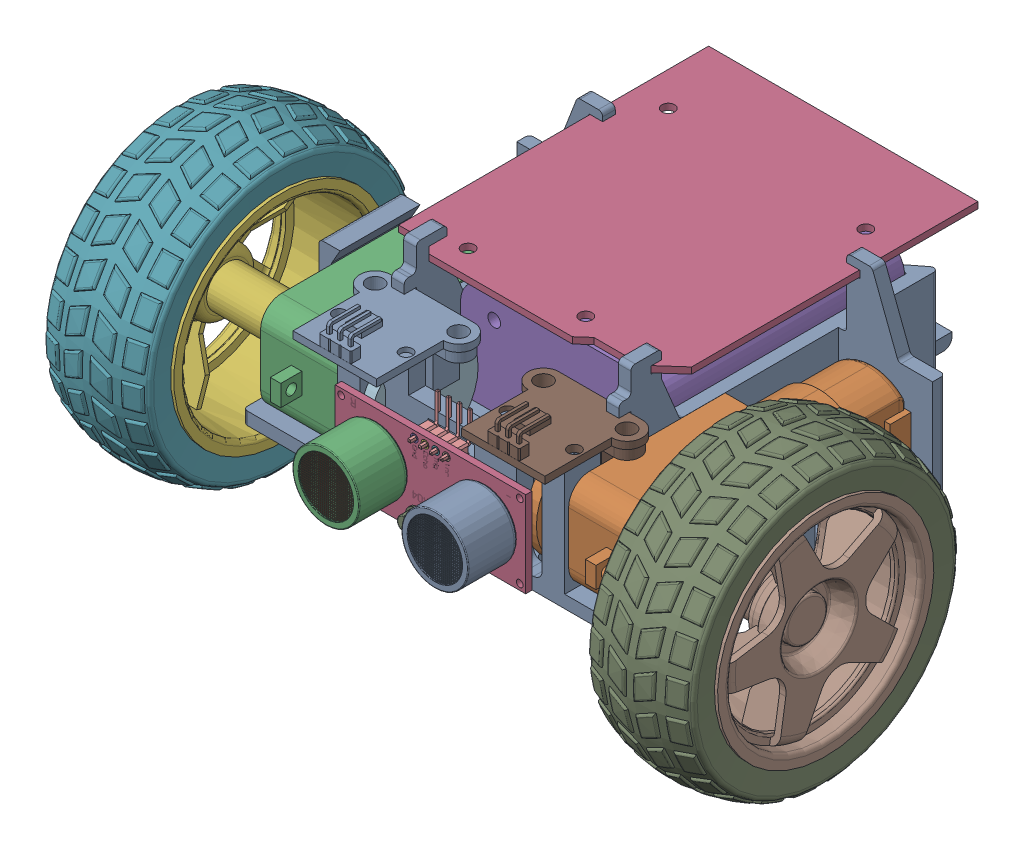
SolidWorks assembly Assem1, configuration Default. Lengths in mm.
Overall size (154.19 96.19 135.99).
12 component instances, 8 part files, 19 mates.
Components (placement in the parent):
- Chassis1-1: Chassis1 [Default] at (2.5551 1.7941 -4.0219) size (98.8 42.03 100)
- motor.step-1: motor.step [Default] at (39.8051 13.0141 0.7067) x (0 1 0) z (0 0 1) size (22.3 37 70.8)
- motor.step-2: motor.step [Default] at (-35.0854 13.0141 0.7067) x (0 -1 0) z (0 0 1) size (22.3 37 70.8)
- Arduino-2: Arduino [Default] at (2.3104 38.4154 -27.7268) x (0 0 -1) z (-1 0 0) size (76 1.5 64)
- Battery-2: Battery [Default] at (2.5551 1.7941 -25.5733) x (0 0 1) z (-1 0 0) size (58 28 47.5)
- Wheel D65x25-1: Wheel D65x25 [По умолчанию] at (-74.7354 13.0141 17.3267) x (0 0.815952 0.578119) z (-1 0 0) size (68.99 69.02 30)
- Wheel D65x25-2: Wheel D65x25 [По умолчанию] at (79.4551 13.0141 17.3267) x (0 0.31276 -0.949832) z (1 0 0) size (68.99 69.02 30)
- HC-SR04-1: HC-SR04 [Default] at (2.9751 12.7511 33.2581) x (-1 0 0) z (0 0 1) size (45.25 26.03 17.8)
- HC_020K-1: HC_020K [Varsayılan] at (22.555 31.3599 25.4767) x (-1 0 0) z (0 -1 0) size (27.15 23.16 17.67)
- EncoderWheel-1: EncoderWheel [Default] at (-16.0152 13.3031 17.3167) x (0 -1 0) z (-1 0 0) size (25.75 25.75 2.55)
- HC_020K-2: HC_020K [Varsayılan] at (-17.4449 31.3599 25.4767) x (-1 0 0) z (0 -1 0) size (27.15 23.16 17.67)
- EncoderWheel-2: EncoderWheel [Default] at (23.5861 13.2266 17.3194) x (0 -1 0) z (-1 0 0) size (25.75 25.75 2.55)
Mates (geometry in assembly coordinates):
- Concentric5: concentric anti-aligned: cylinder of motor.step-2 through (-44.7354 13.0141 17.3267) axis (1 0 0) radius 2.7; circle of Wheel D65x25-1
- Coincident2: coincident anti-aligned: plane of motor.step-2 through (-44.7354 13.0141 17.3267) normal (-1 0 0); plane of Wheel D65x25-1 through (-44.7354 13.0141 17.3267) normal (1 0 0)
- Concentric6: concentric anti-aligned: cylinder of motor.step-1 through (49.4551 13.0141 17.3267) axis (-1 0 0) radius 2.7; cylinder of Wheel D65x25-2 through (79.4551 13.0141 17.3267) axis (1 0 0) radius 2.75
- Coincident3: coincident anti-aligned: plane of motor.step-1 through (49.4551 13.0141 17.3267) normal (1 0 0); plane of Wheel D65x25-2 through (49.4551 13.0141 17.3267) normal (-1 0 0)
- Parallel2: parallel anti-aligned: line of Chassis1-1 through (-39.3877 24.1941 -38.5733) axis (-1 0 0); line of motor.step-2 through (-43.6354 24.1641 -8.6933) axis (1 0 0)
- Parallel3: parallel aligned: line of Chassis1-1 through (44.4979 24.1941 -38.5733) axis (1 0 0); line of motor.step-1 through (29.5551 24.1641 -8.6933) axis (1 0 0)
- Parallel7: parallel aligned: cylinder of Chassis1-1 through (27.5551 13.0141 6.1767) axis (1 0 0) radius 2.05; cylinder of motor.step-1 through (28.5551 13.0141 6.1767) axis (1 0 0) radius 1.75
- Concentric13: concentric aligned: cylinder of Chassis1-1 through (27.5551 13.0141 6.1767) axis (1 0 0) radius 2.05; cylinder of motor.step-1 through (28.5551 13.0141 6.1767) axis (1 0 0) radius 1.75
- Concentric14: concentric aligned: cylinder of Chassis1-1 through (-22.4449 13.0141 6.1767) axis (-1 0 0) radius 2.05; cylinder of motor.step-2 through (-23.8354 13.0141 6.1767) axis (-1 0 0) radius 1.75
- Coincident4: coincident anti-aligned: circle of Chassis1-1; circle of Battery-2
- Parallel8: parallel aligned: line of Chassis1-1 through (21.5551 1.7941 -70.5733) axis (-1 0 0); line of Battery-2 through (20.3051 1.7941 -54.5733) axis (-1 0 0)
- Parallel10: parallel anti-aligned: plane of motor.step-1 through (20.4551 14.9807 15.4767) normal (0 0 -1); plane of EncoderWheel-1 through (-25.133 16.0231 15.4767) normal (0 0 1)
- Coincident9: coincident anti-aligned: plane of Chassis1-1 through (29.5551 24.1941 -35.5733) normal (1 0 0); plane of motor.step-1 through (29.5551 6.8641 23.5067) normal (-1 0 0)
- Coincident11: coincident anti-aligned: plane of motor.step-1 through (20.4551 14.9807 15.4767) normal (0 0 -1); plane of EncoderWheel-1 through (-25.133 16.0231 15.4767) normal (0 0 1)
- Coincident12: coincident anti-aligned: plane of Chassis1-1 through (34.5551 13.0141 14.4267) normal (0 0 1); plane of HC_020K-1 through (32.48 27.0599 14.4267) normal (0 0 -1)
- Coincident13: coincident anti-aligned: plane of Chassis1-1 through (-29.4449 13.0141 14.4267) normal (0 0 1); plane of HC_020K-2 through (-7.5199 27.0599 14.4267) normal (0 0 -1)
- Coincident14: coincident aligned: plane of Chassis1-1 through (29.5551 24.1941 -35.5733) normal (1 0 0); plane of HC_020K-1 through (29.5551 18.5599 14.4267) normal (1 0 0)
- Coincident15: coincident aligned: plane of Chassis1-1 through (-24.4449 24.1941 -35.5733) normal (-1 0 0); plane of HC_020K-2 through (-24.4449 18.5599 14.4267) normal (-1 0 0)
- Coincident18: coincident anti-aligned: plane of Chassis1-1 through (8.0551 -1.2059 19.4267) normal (-1 0 0); plane of HC-SR04-1 through (8.0551 21.4011 31.9482) normal (1 0 0)
